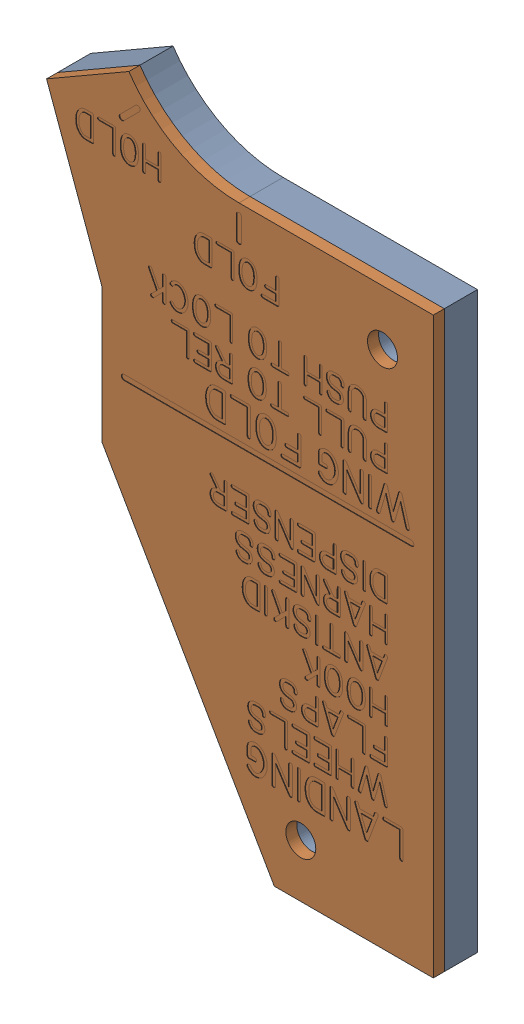
SolidWorks assembly LDG CKLST - WING FOLD Placard, configuration Default. Lengths in mm.
Overall size (55.61 91 6.35).
2 component instances, 2 part files, 0 mates.
Components (placement in the parent):
- LDG - WING FOLD Placard Lightplate-1: LDG - WING FOLD Placard Lightplate [Default] at origin size (55.61 91 4.76)
- LDG - WING FOLD Placard Legend Plate-1: LDG - WING FOLD Placard Legend Plate [Default] at (0 0 4.7625) size (55.61 91 1.59)
